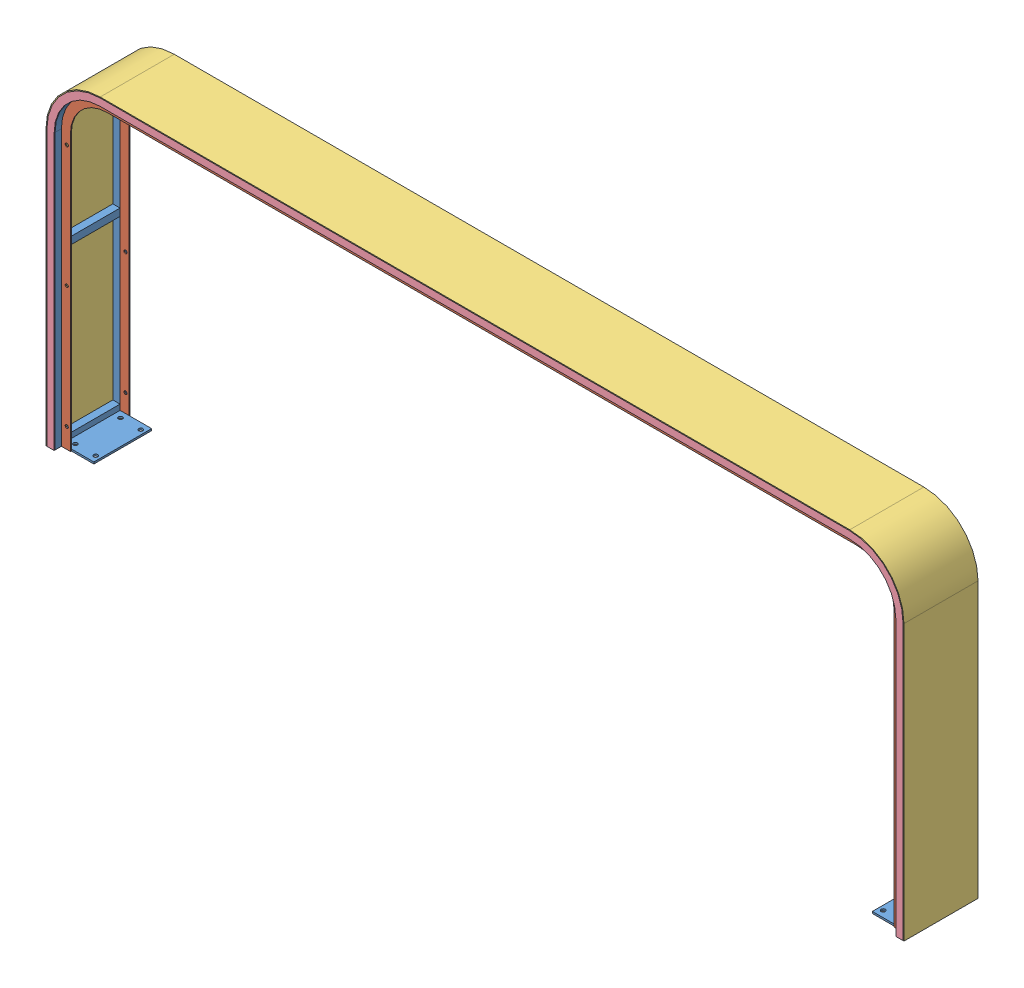
SolidWorks assembly wallFrame, configuration Default. Lengths in mm.
Overall size (1900 729 164).
6 component instances, 4 part files, 3 mates.
Components (placement in the parent):
- table-wallFrame-bone-1: table-wallFrame-bone [Default] at origin size (1896 727 160)
- table-wallFrame-Ufix-1: table-wallFrame-Ufix [Default] at origin size (1864 711 2)
- table-wallFrame-sideshell-1: table-wallFrame-sideshell [Default] at origin size (1900 729 164)
- table-wallFrame-Ushell-1: table-wallFrame-Ushell [Default] at (0 0 -162) size (1896 727 2)
- table-wallFrame-Ufix-2: table-wallFrame-Ufix [Default] at (0 0 130) size (1864 711 2)
- table-wallFrame-Ushell-2: table-wallFrame-Ushell [Default] at origin size (1896 727 2)
Mates (geometry in assembly coordinates):
- 重合1: coincident anti-aligned: plane of table-wallFrame-bone-1 through (830 580 -80) normal (0 0 -1); plane of table-wallFrame-Ushell-1 through (830 580 -80) normal (0 0 1)
- 重合2: coincident aligned: plane of table-wallFrame-bone-1 through (-932 -29 -64) normal (0 -1 0); plane of table-wallFrame-Ushell-1 through (-948 -29 -82) normal (0 -1 0)
- 重合3: coincident aligned: plane of table-wallFrame-bone-1 through (-932 -29 -64) normal (1 0 0); plane of table-wallFrame-Ushell-1 through (-932 -29 -82) normal (1 0 0)
